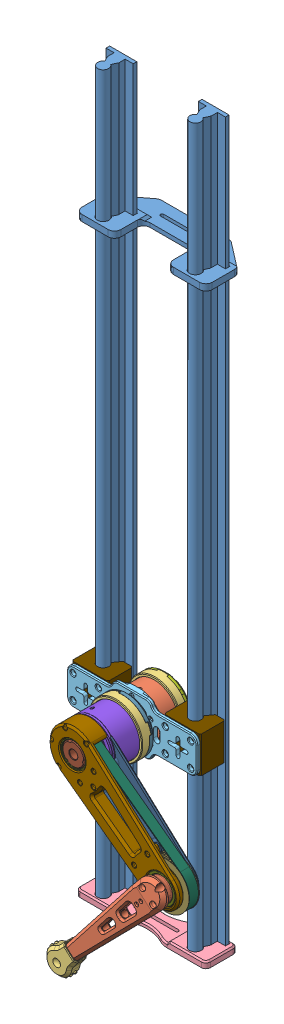
SolidWorks assembly Two DOF Jumping Stand 012, configuration Default. Lengths in mm.
Overall size (212.83 804.86 151.72).
37 component instances, 25 part files, 20 mates.
Components (placement in the parent):
- Linear Rail 8000mm-1: Linear Rail 8000mm [Default] at (133.2022 813.2855 706.0361) x (1 0 0) z (0 0 -1) size (30 800 28.2)
- Linear Rail 8000mm-2: Linear Rail 8000mm [Default] at (235.2022 813.2855 706.0361) x (1 0 0) z (0 0 -1) size (30 800 28.2)
- J2 010-1: J2 010 [Default] at (166.3876 191.4526 671.5737) size (70 59 38.4)
  - Servo (wo front plate) 010-1: Servo (wo front plate) 010 [Default] at (17.7375 29.5761 27.1952) size (52.8 52.8 26)
  - J2 Front Plate 100-1: J2 Front Plate 100 [Default] at (17.7375 29.5761 49.1952) size (70 57.5 6) (hidden)
  - Back Plate 100-1: Back Plate 100 [Default] at (17.7375 29.5761 28.9452) x (1 0 0) z (0 1 0) size (59 10.25 58.73)
  - Magnet Holder 100-1: Magnet Holder 100 [Default] at (17.7375 29.5761 33.7452) x (0.637878 -0.770138 0) z (0 0 -1) size (9 9 8.25)
  - Dagor Controller 2.5-1: Dagor Controller 2.5 [Default] at (-33.0562 -36.3481 -63.7332) size (44 44 7.5)
    - Dagor Controller Board 2.5-1: Dagor Controller Board 2.5 [Predeterminado] at (50.7937 65.9242 86.1284) size (44 44 7.5)
    - ESP32-WROOM-32U-1: ESP32-WROOM-32U [Default] at (44.7937 81.3242 85.1634) x (1 0 0) z (0 0 -1) size (18.07 19.38 3.04)
  - J2 Back Plate B 015-1: J2 Back Plate B 015 [Default] at (17.7375 29.5761 20.6952) x (-1 0 0) z (0 0 -1) size (59 59 5.9)
- J3 010-1: J3 010 [Default] at (180.0308 188.998 712.3116) x (0.936781 0.349917 0) z (0 0 1) size (133.15 179.12 66.24)
  - GIM4310-1: GIM4310 [Default] at (15.0435 28.5731 29.2983) size (52.8 52.8 31)
  - Femur 102-1: Femur 102 [Default] at (15.0435 28.5731 78.6983) x (0.866025 0.5 0) z (0 0 1) size (53 172.1 19.5)
  - Femur B 100-1: Femur B 100 [Default] at (15.0435 28.5731 53.6983) x (-0.866025 -0.5 0) z (0 0 -1) size (52.55 140.58 14.5)
  - Pulley A 22T 100-1: Pulley A 22T 100 [Predeterminado] at (15.0435 28.5731 71.3983) x (-1 0 0) z (0 0 -1) size (36.31 36.31 17.35)
  - Pulley B 30T 100-2: Pulley B 30T 100 [Predeterminado] at (77.8435 -80.1997 61.0483) x (0.332342 0.943159 0) z (0 0 1) size (50.61 50.61 20.55)
  - Pulley B Plate 011-1: Pulley B Plate 011 [Default] at (77.8435 -80.1997 54.7983) x (-0.332342 -0.943159 0) z (0 0 -1) size (27 27 6.5)
  - Back Plate 100-1: Back Plate 100 [Default] at (15.0435 28.5731 31.0483) x (1 0 0) z (0 1 0) size (59 10.25 58.73)
  - Back Plate B 100-1: Back Plate B 100 [Default] at (15.0435 28.5731 22.7073) x (-1 0 0) z (0 0 -1) size (59 59 10.25)
  - Belt 380mm 010-1: Belt 380mm 010 [Default] at (77.8435 -80.1997 71.1483) x (-0.5 0.866025 0) z (-0.866025 -0.5 0) size (168.8 10 50)
  - 6705 Bearing-1: 6705 Bearing [Predeterminado] at (77.8435 -80.1997 75.7483) x (0.784247 0.620449 0) z (0.620449 -0.784247 0) size (32 4.1 32)
  - 6705 Bearing-2: 6705 Bearing [Predeterminado] at (77.8435 -80.1997 56.3983) x (0.58942 -0.807827 0) z (-0.807827 -0.58942 0) size (32 4.1 32)
  - 6705 Bearing-3: 6705 Bearing [Predeterminado] at (15.0435 28.5731 75.3983) x (0.99524 0.097458 0) z (0.097458 -0.99524 0) size (32 4.1 32)
  - Dagor Controller Board 2.5-1: Dagor Controller Board 2.5 [Predeterminado] at (15.0435 28.5731 24.4983) size (44 44 7.5)
  - ESP32-WROOM-32U-1: ESP32-WROOM-32U [Default] at (9.0435 43.9731 23.5333) x (1 0 0) z (0 0 -1) size (18.07 19.38 3.04)
  - Magnet Holder 100-1: Magnet Holder 100 [Default] at (15.0435 28.5731 35.6983) x (-0.895065 0.445935 0) z (0 0 -1) size (9 9 8.25)
  - Dagor PCB 2.1-1: Dagor PCB 2.1 [Predeterminado] at (15.0323 28.6036 24.5346) size (54.75 44 9.7) (hidden)
  - Header Female 2x4 pos-2: Header Female 2x4 pos [Default] at (-10.6951 37.8149 27.8098) x (0 -1 0) z (1 0 0) size (10.67 7.49 8.56)
  - Header Female 2x4 pos-3: Header Female 2x4 pos [Default] at (-10.6659 37.7629 20.3251) x (0 1 0) z (1 0 0) size (10.67 7.49 8.56)
- Linear Bearing 40x40mm 12mm-1: Linear Bearing 40x40mm 12mm [Default] at (133.2022 220.9651 693.1689) x (1 0 0) z (0 -1 0) size (40 27.6 40)
- Linear Bearing 40x40mm 12mm-2: Linear Bearing 40x40mm 12mm [Default] at (235.2022 220.9651 693.1689) x (1 0 0) z (0 -1 0) size (40 27.6 40)
- Rail Space 010-1: Rail Space 010 [Default] at (184.2022 661.4005 697.9448) x (-1 0 0) z (0 0 -1) size (144 7 60)
- Low Limb 022-1: Low Limb 022 [Predeterminado] at (281.0163 141.1072 805.6599) x (-0.750946 0.660363 0) z (0 0 -1) size (30 174.81 21)
- Sock 012-1: Sock 012 [Default] at (182.9523 29.5917 799.6599) x (0.750946 -0.660363 0) z (0 0 1) size (30 35.47 15)
- Top Rail Space 010-1: Top Rail Space 010 [Default] at (184.2022 13.2855 697.9448) x (-1 0 0) z (0 0 -1) size (144 7 35)
- Jump Stand J2 Front Plate 100-1: Jump Stand J2 Front Plate 100 [Default] at (184.125 221.0287 720.7689) size (144 57.5 6.5)
Mates (geometry in assembly coordinates):
- Coincident1: coincident aligned: plane of Linear Rail 8000mm-1 through (133.2022 813.2855 706.0361) normal (0 1 0); plane of Linear Rail 8000mm-2 through (235.2022 813.2855 706.0361) normal (0 1 0)
- Concentric1: concentric anti-aligned: cylinder of J2 010-1/Servo (wo front plate) 010-1 through (184.125 221.0287 721.6689) axis (0 0 1) radius 4; cylinder of J3 010-1/GIM4310-1 through (184.125 221.0287 771.5099) axis (0 0 -1) radius 26.4
- Coincident3: coincident anti-aligned: plane of J2 010-1/Servo (wo front plate) 010-1 through (184.125 221.0287 724.7689) normal (0 0 1); plane of J3 010-1/Back Plate B 100-1 through (184.125 221.0287 724.7689) normal (0 0 -1)
- Coincident4: coincident anti-aligned: plane of J2 010-1/J2 Front Plate 100-1 through (184.125 221.0287 720.7689) normal (0 0 -1); plane of Linear Bearing 40x40mm 12mm-2 through (235.2022 220.9651 720.7689) normal (0 0 1)
- Coincident5: coincident anti-aligned: plane of J2 010-1/J2 Front Plate 100-1 through (184.125 221.0287 720.7689) normal (0 0 -1); plane of Linear Bearing 40x40mm 12mm-1 through (133.2022 220.9651 720.7689) normal (0 0 1)
- Concentric6: concentric anti-aligned: cylinder of Linear Rail 8000mm-1 through (133.2022 13.2855 706.0361) axis (0 1 0) radius 6; cylinder of Linear Bearing 40x40mm 12mm-1 through (133.2022 240.9651 706.0361) axis (0 -1 0) radius 6.25
- Concentric7: concentric anti-aligned: cylinder of Linear Rail 8000mm-2 through (235.2022 13.2855 706.0361) axis (0 1 0) radius 6; cylinder of Linear Bearing 40x40mm 12mm-2 through (235.2022 240.9651 706.0361) axis (0 -1 0) radius 6.25
- Coincident6: coincident aligned: plane of Linear Rail 8000mm-1 through (118.2022 13.2855 683.8361) normal (0 0 -1); plane of Linear Rail 8000mm-2 through (220.2022 13.2855 683.8361) normal (0 0 -1)
- Concentric8: concentric anti-aligned: cylinder of Linear Rail 8000mm-1 through (133.2022 13.2855 706.0361) axis (0 1 0) radius 6; cylinder of Rail Space 010-1 through (133.2022 668.4005 706.0361) axis (0 -1 0) radius 6.5
- Concentric9: concentric anti-aligned: cylinder of Linear Rail 8000mm-2 through (235.2022 13.2855 706.0361) axis (0 1 0) radius 6; cylinder of Rail Space 010-1 through (235.2022 668.4005 706.0361) axis (0 -1 0) radius 6.5
- Concentric10: concentric anti-aligned: cylinder of J3 010-1/6705 Bearing-1 through (281.0163 141.1072 790.0599) axis (0 0 -1) radius 12.5; cylinder of Low Limb 022-1 through (281.0163 141.1072 789.6599) axis (0 0 1) radius 12.5
- Coincident8: coincident anti-aligned: plane of J3 010-1/Pulley B 30T 100-2 through (281.0163 141.1072 789.6599) normal (0 0 1); plane of Low Limb 022-1 through (281.0163 141.1072 789.6599) normal (0 0 -1)
- Width1: width anti-aligned: plane of Low Limb 022-1 through (269.214 150.365 793.6599) normal (-0.786818 0.617185 0); plane of Low Limb 022-1 through (291.7069 130.5853 793.6599) normal (0.712708 -0.701461 0); plane of Sock 012-1 through (190.2362 50.3334 807.1599) normal (0.71418 -0.699962 0); plane of Sock 012-1 through (202.5926 39.4675 807.1599) normal (-0.78552 0.618836 0)
- Width2: width anti-aligned: plane of Sock 012-1 through (206.3799 25.6917 793.6599) normal (0 0 1); plane of Sock 012-1 through (206.3799 25.6917 805.6599) normal (0 0 -1); plane of Low Limb 022-1 through (281.0163 141.1072 793.6599) normal (0 0 -1); plane of Low Limb 022-1 through (281.0163 141.1072 805.6599) normal (0 0 1)
- Concentric11: concentric aligned: cylinder of Low Limb 022-1 through (182.9523 29.5917 803.6599) axis (0 0 -1) radius 10.1; cylinder of Sock 012-1 through (182.9523 29.5917 807.1599) axis (0 0 -1) radius 12.25
- Concentric12: concentric anti-aligned: cylinder of Linear Rail 8000mm-2 through (235.2022 13.2855 706.0361) axis (0 1 0) radius 6; cylinder of Top Rail Space 010-1 through (235.2022 20.2855 706.0361) axis (0 -1 0) radius 6.5
- Concentric13: concentric anti-aligned: cylinder of Linear Rail 8000mm-1 through (133.2022 13.2855 706.0361) axis (0 1 0) radius 6; cylinder of Top Rail Space 010-1 through (133.2022 20.2855 706.0361) axis (0 -1 0) radius 6.5
- Coincident9: coincident aligned: plane of Linear Rail 8000mm-1 through (133.2022 13.2855 706.0361) normal (0 -1 0); plane of Top Rail Space 010-1 through (184.2022 13.2855 697.9448) normal (0 -1 0)
- Coincident10: coincident anti-aligned: plane of Linear Bearing 40x40mm 12mm-2 through (235.2022 220.9651 720.7689) normal (0 0 1); plane of Jump Stand J2 Front Plate 100-1 through (184.125 221.0287 720.7689) normal (0 0 -1)
- Concentric14: concentric anti-aligned: cylinder of J2 010-1/Servo (wo front plate) 010-1 through (184.125 221.0287 723.6689) axis (0 0 -1) radius 26.4; cylinder of Jump Stand J2 Front Plate 100-1 through (184.125 221.0287 718.7689) axis (0 0 1) radius 27
